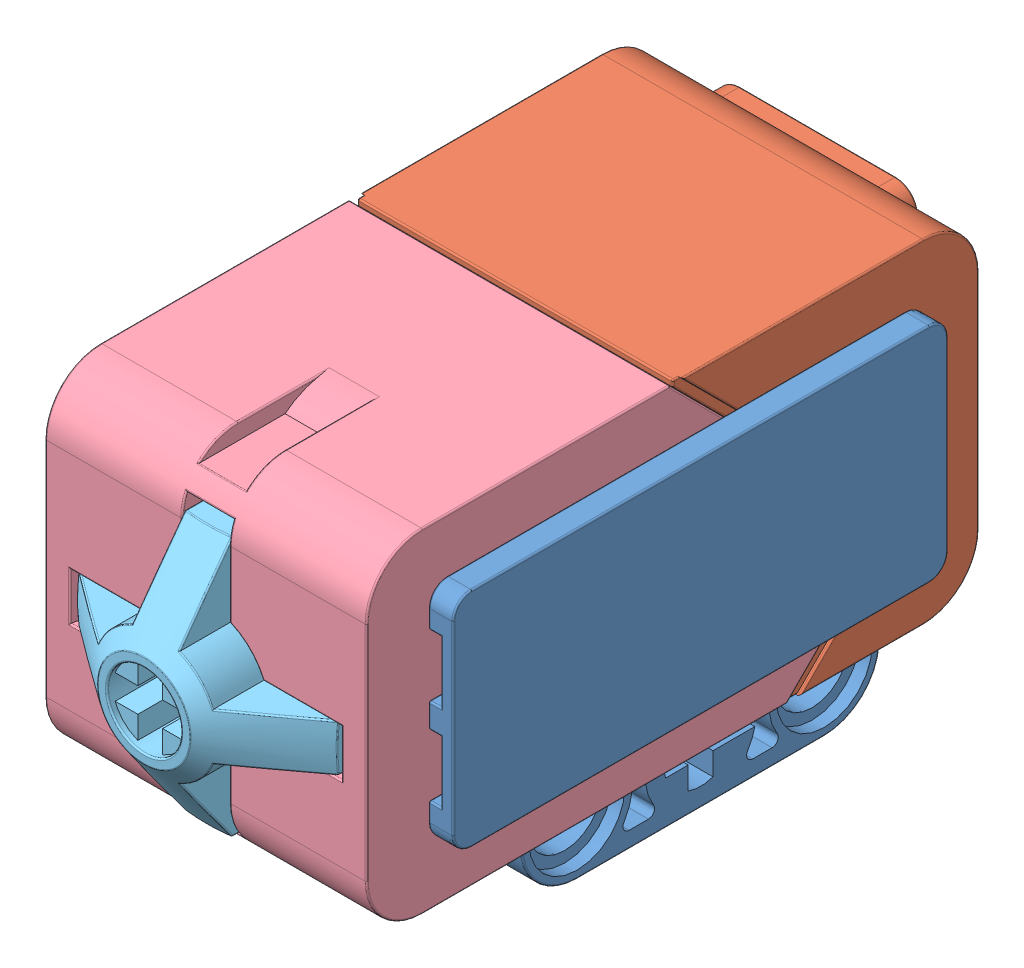
SolidWorks assembly 95648, configuration Default. Lengths in mm.
Overall size (24 31.05 43.62).
7 component instances, 5 part files, 0 mates.
Components (placement in the parent):
- 95648.stp-1: 95648.stp [Default] at origin size (24 31.05 43.62)
  - 99385c01.stp-1: 99385c01.stp [Default] at origin size (24 31.05 39.62)
    - 99377-LtBluishGray.stp-1: 99377-LtBluishGray.stp [Default] at origin size (24 29.6 38)
    - 99376-White.stp-1: 99376-White.stp [Default] at (0 0.44 -14.2) size (22.3 23.6 19.62)
    - 54732b-LtBluishGray.stp-1: 54732b-LtBluishGray.stp [Default] at (0 2.04 -20.2) x (-1 0 0) z (0 0 -1) size (12 14.56 14.4)
    - 99385-LtBluishGray.stp-1: 99385-LtBluishGray.stp [Default] at (0 0.44 13.8) size (22.4 21.61 30.66)
  - 99386-Red.stp-1: 99386-Red.stp [Default] at (0 -0.36 15.4) size (18.23 16.99 14.8)
